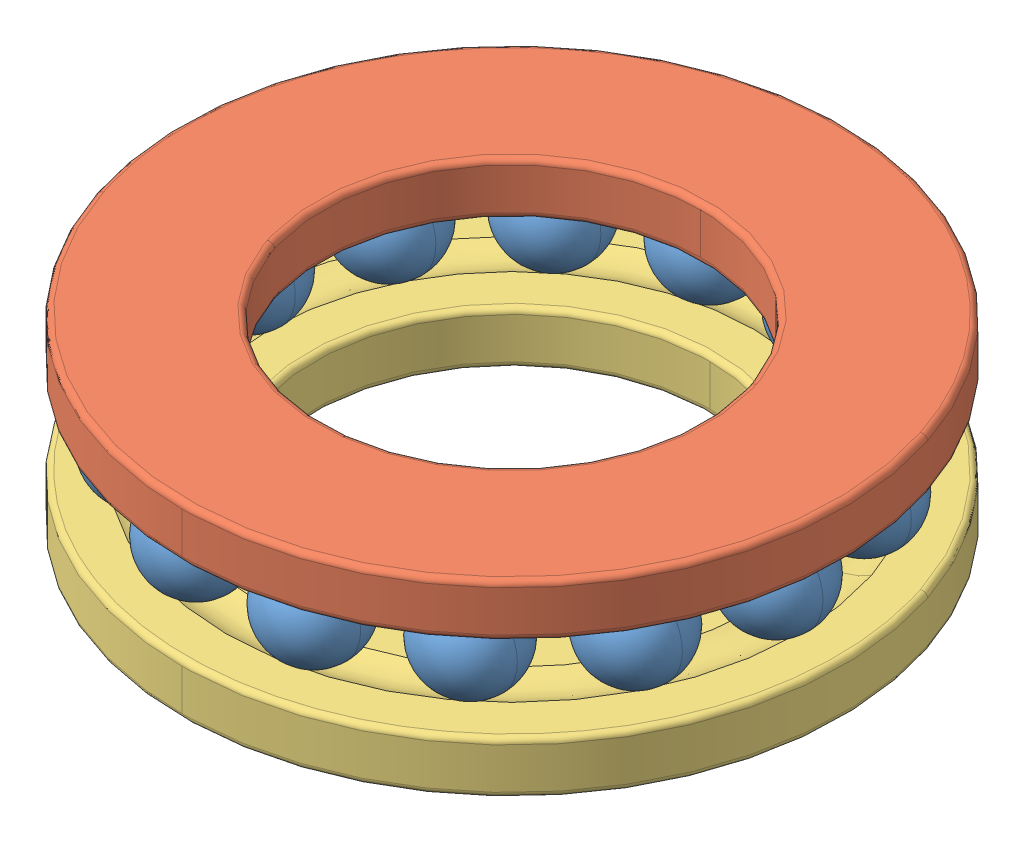
SolidWorks assembly 51104, configuration 51104 20MM THRUST BEARING. Lengths in mm.
Overall size (35 10 35).
16 component instances, 3 part files, 0 mates.
Components (placement in the parent):
- 51104_3-1: 51104_3 [Default] at (-12.6136 5 -6.0744) x (0 -1 0) z (0 0 1) size (5 5 5)
- 51104_3-2: 51104_3 [Default] at (-8.7289 5 -10.9456) x (0 -1 0) z (0 0 1) size (5 5 5)
- 51104_3-3: 51104_3 [Default] at (-3.1153 5 -13.649) x (0 -1 0) z (0 0 1) size (5 5 5)
- 51104_3-4: 51104_3 [Default] at (3.1153 5 -13.649) x (0 -1 0) z (0 0 1) size (5 5 5)
- 51104_3-5: 51104_3 [Default] at (8.7289 5 -10.9456) x (0 -1 0) z (0 0 1) size (5 5 5)
- 51104_3-6: 51104_3 [Default] at (12.6136 5 -6.0744) x (0 -1 0) z (0 0 1) size (5 5 5)
- 51104_3-7: 51104_3 [Default] at (14 5 0) x (0 -1 0) z (0 0 1) size (5 5 5)
- 51104_3-8: 51104_3 [Default] at (12.6136 5 6.0744) x (0 -1 0) z (0 0 1) size (5 5 5)
- 51104_3-9: 51104_3 [Default] at (8.7289 5 10.9456) x (0 -1 0) z (0 0 1) size (5 5 5)
- 51104_3-10: 51104_3 [Default] at (3.1153 5 13.649) x (0 -1 0) z (0 0 1) size (5 5 5)
- 51104_3-11: 51104_3 [Default] at (-3.1153 5 13.649) x (0 -1 0) z (0 0 1) size (5 5 5)
- 51104_3-12: 51104_3 [Default] at (-8.7289 5 10.9456) x (0 -1 0) z (0 0 1) size (5 5 5)
- 51104_3-13: 51104_3 [Default] at (-12.6136 5 6.0744) x (0 -1 0) z (0 0 1) size (5 5 5)
- 51104_3-14: 51104_3 [Default] at (-14 5 0) x (0 -1 0) z (0 0 1) size (5 5 5)
- 51104_18-1: 51104_18 [Default] at (0 7.2222 0) x (0 1 0) z (0 0 1) size (2.78 35 35)
- 51104_20-1: 51104_20 [Default] at origin size (35 2.78 35)
